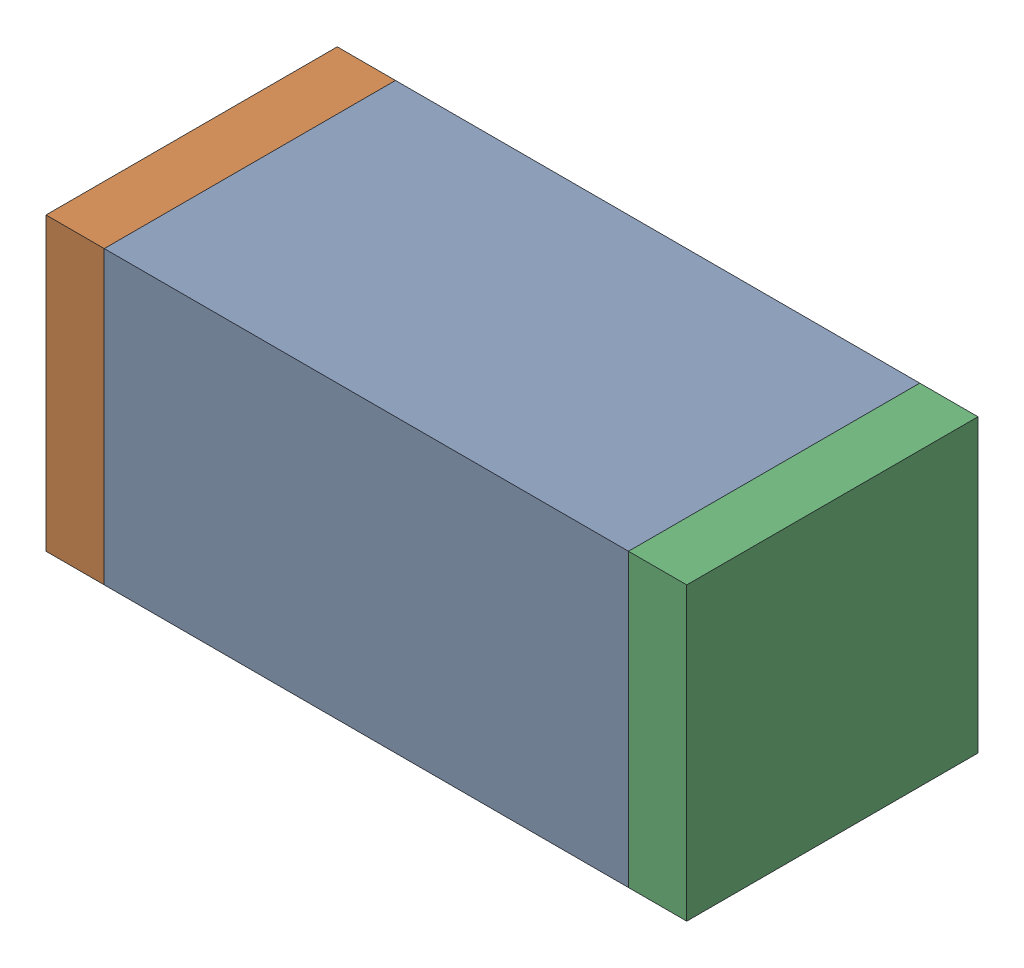
SolidWorks assembly C2, configuration Default. Lengths in mm.
Overall size (1.1 0.5 0.5).
6 component instances, 2 part files, 0 mates.
Components (placement in the parent):
- 836749680-1: 836749680 [Default] at (104.3 7.45 0) size (0.9 0.5 0.5)
  - Extruded_4-1: Extruded_4 [Default] at origin size (0.9 0.5 0.5)
- 810156080-1: 810156080 [Default] at (103.8 7.45 0) size (0.1 0.5 0.5)
  - Extruded_5-1: Extruded_5 [Default] at origin size (0.1 0.5 0.5)
- 810156080-2: 810156080 [Default] at (104.8 7.45 0) size (0.1 0.5 0.5)
  - Extruded_5-1: Extruded_5 [Default] at origin size (0.1 0.5 0.5)
